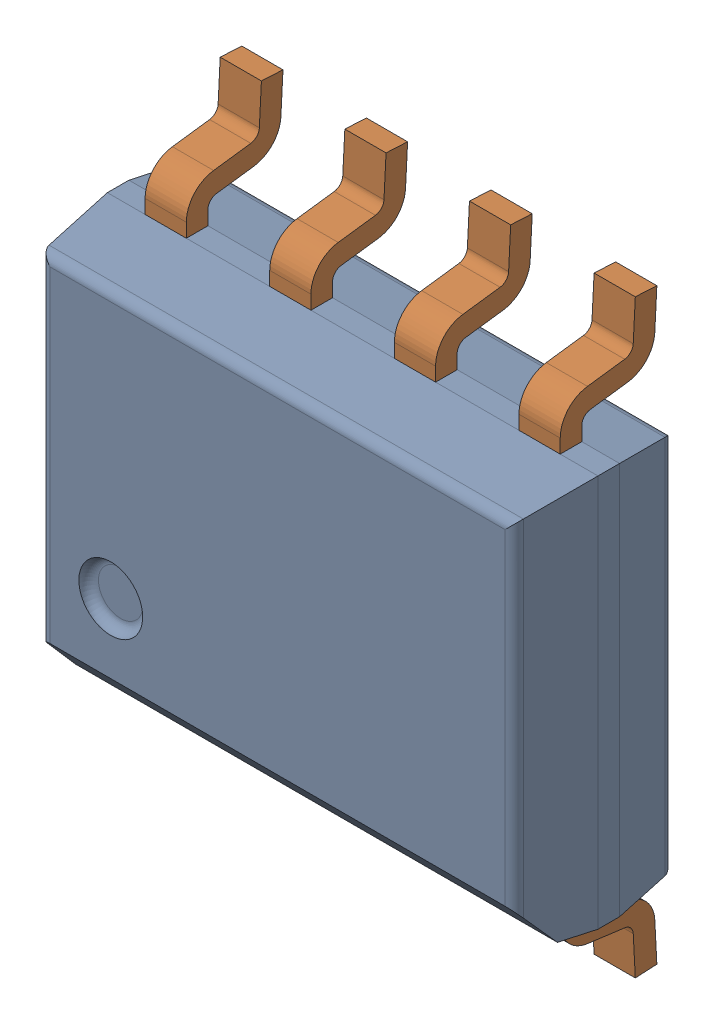
SolidWorks assembly IC1, configuration Default. Lengths in mm.
Overall size (5 6.01 1.75).
3 component instances, 2 part files, 0 mates.
Components (placement in the parent):
- User_Library-SOIC-8-1: User_Library-SOIC-8 [Default] at (31.4305 22.4028 0) x (1 0 0) z (0 -1 0) size (5 1.75 6.01)
  - User_Library-SOIC-8_SOIC-8_Body_1-1: User_Library-SOIC-8_SOIC-8_Body_1 [Default] at origin size (5 1.6 4)
  - User_Library-SOIC-8_SOIC-8_Pins_1-1: User_Library-SOIC-8_SOIC-8_Pins_1 [Default] at origin size (4.23 0.99 6.01)
